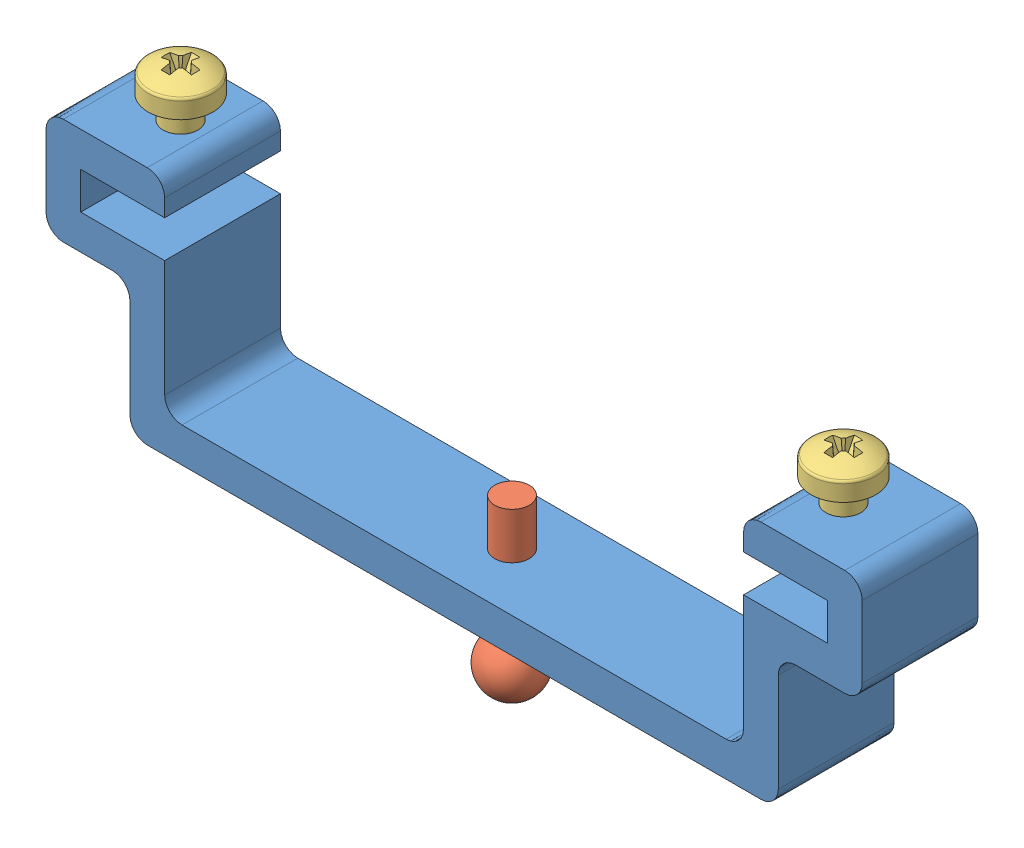
SolidWorks assembly Assembly schuiver M3 ronde kop, configuration Default. Lengths in mm.
Overall size (70.5 33.1 10).
4 component instances, 3 part files, 11 mates.
Components (placement in the parent):
- M3 ronde kop schuiver-1: M3 ronde kop schuiver [Default] at (0 0 -5) size (70.5 20.75 10)
- M3 ronde kop-1: M3 ronde kop [Default] at (0 -17.75 0) size (5.77 15 5)
- pan head cross recess screw_iso-1: pan head cross recess screw_iso [ISO 7045 - M3 x 5 - Z - 5N] at (28.625 7.4 0) x (0 -1 0) z (0 0 1) size (7.35 5.6 5.6)
- pan head cross recess screw_iso-2: pan head cross recess screw_iso [ISO 7045 - M3 x 5 - Z - 5N] at (-28.625 7.4 0) x (0 -1 0) z (0 0 1) size (7.35 5.6 5.6)
Mates (geometry in assembly coordinates):
- Coincident1: coincident aligned: plane of M3 ronde kop schuiver-1 through (0 0 -5) normal (1 0 0)
- Coincident2: coincident aligned: plane of M3 ronde kop schuiver-1 through (0 0 -5) normal (0 1 0)
- Concentric1: concentric anti-aligned: cylinder of M3 ronde kop schuiver-1 through (0 -17.75 0) axis (0 1 0) radius 1.25; cylinder of M3 ronde kop-1 through (0 -25.75 0) axis (0 -1 0) radius 1.5
- Parallel1: parallel aligned: plane of M3 ronde kop schuiver-1 through (0 0 5) normal (0 0 1); plane of M3 ronde kop-1 through (-1.4434 -19.75 2.5) normal (0 0 1)
- Coincident5: coincident anti-aligned: plane of M3 ronde kop schuiver-1 through (28 -17.75 5) normal (0 -1 0); plane of M3 ronde kop-1 through (0 -17.75 -1.5) normal (0 1 0)
- Coincident6: coincident aligned: plane of M3 ronde kop-1 through (0 -17.75 0) normal (0 0 1)
- Coincident7: coincident aligned: plane of pan head cross recess screw_iso-1 through (30.125 0 0) normal (0 -1 0); plane of pan head cross recess screw_iso-2 through (-27.125 0 0) normal (0 -1 0)
- Coincident8: coincident aligned: plane of M3 ronde kop schuiver-1 through (-25 0 5) normal (0 -1 0); plane of pan head cross recess screw_iso-2 through (-27.125 0 0) normal (0 -1 0)
- Coincident9: coincident aligned: plane of pan head cross recess screw_iso-1 through (29.1525 5.65 -0.37) normal (0 0 1); plane of pan head cross recess screw_iso-2 through (-28.0975 5.65 -0.37) normal (0 0 1)
- Concentric2: concentric aligned: cylinder of M3 ronde kop schuiver-1 through (-28.625 -17.751 0) axis (0 1 0) radius 1.25; cylinder of pan head cross recess screw_iso-2 through (-28.625 32.8 0) axis (0 1 0) radius 1.5
- Concentric3: concentric aligned: cylinder of M3 ronde kop schuiver-1 through (28.625 -17.751 0) axis (0 1 0) radius 1.25; cylinder of pan head cross recess screw_iso-1 through (28.625 32.8 0) axis (0 1 0) radius 1.5
